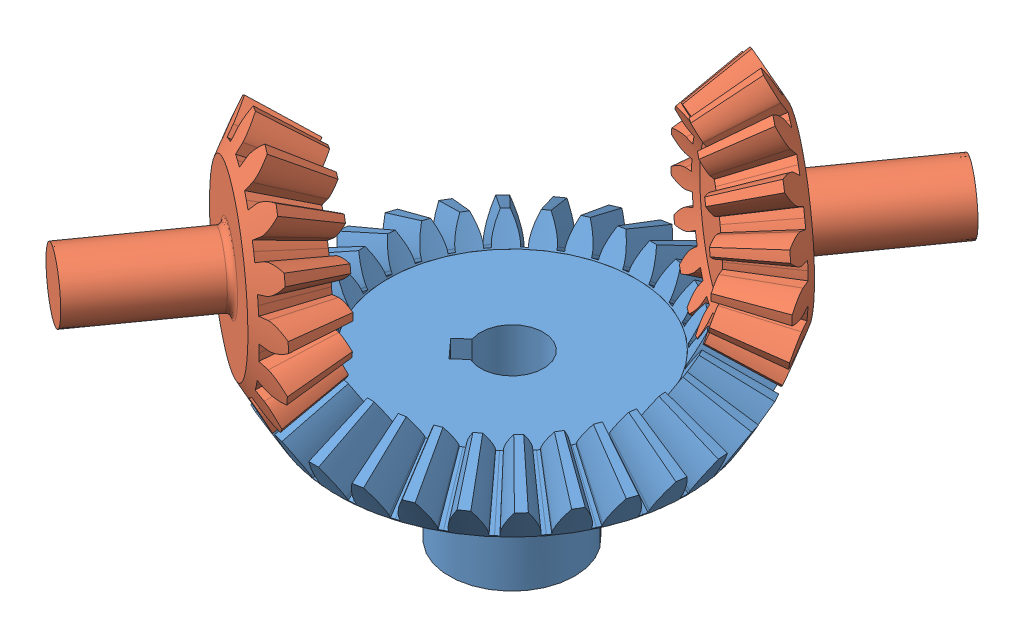
SolidWorks assembly ASSEMBLY Bevel Gear Test Attemp 2, configuration Default. Lengths in mm.
Overall size (97.27 65.52 111.02).
3 component instances, 2 part files, 9 mates.
Components (placement in the parent):
- Secondary Main Bevel Gear-1: Secondary Main Bevel Gear [Default] at (0 3.8971 0) x (0.672356 0 0.740228) z (-0.740228 0 0.672356) size (61.9 30.12 62)
- Secondary Bevel Gear Right-1: Secondary Bevel Gear Right [Default] at (-17.3371 21.2176 24.3333) x (0.263372 -0.946268 0.187648) z (0.770666 0.323383 0.549088) size (38.4 31.9 38.26)
- Secondary Bevel Gear Right-2: Secondary Bevel Gear Right [Default] at (17.3371 21.2176 -24.3333) x (-0.054416 -0.997765 -0.038771) z (-0.812607 0.066815 -0.57897) size (38.4 31.9 38.26)
Mates (geometry in assembly coordinates):
- Coincident7: coincident: point of Secondary Main Bevel Gear-1; point of Secondary Bevel Gear Right-1
- Perpendicular2: perpendicular: line of Secondary Main Bevel Gear-1 through (69.282 0 21.2176) axis (0 0 -1); line of Secondary Bevel Gear Right-1 through (0 21.2176 0) axis (-0.580267 0 0.814427)
- GearMate1: gear = 60 : 34.5 mm: circle of Secondary Bevel Gear Right-1; circle of Secondary Main Bevel Gear-1
- Coincident9: coincident: point of Secondary Main Bevel Gear-1; point of Secondary Bevel Gear Right-2
- Perpendicular3: perpendicular: line of Secondary Main Bevel Gear-1 through (69.282 0 21.2176) axis (0 0 -1); line of Secondary Bevel Gear Right-2 through (0 21.2176 0) axis (0.580267 0 -0.814427)
- Coincident11: coincident anti-aligned: line of Secondary Bevel Gear Right-1 through (0 21.2176 0) axis (-0.580267 0 0.814427); line of Secondary Bevel Gear Right-2 through (0 21.2176 0) axis (0.580267 0 -0.814427)
- GearMate2: gear = 60 : 34.5 mm: circle of Secondary Bevel Gear Right-2; circle of Secondary Main Bevel Gear-1
- Coincident12: coincident anti-aligned: plane of Secondary Main Bevel Gear-1 through (0 0 0) normal (0 -1 0)
- Coincident13: coincident: line of Secondary Main Bevel Gear-1 through (69.282 0 21.2176) axis (0 0 -1)
